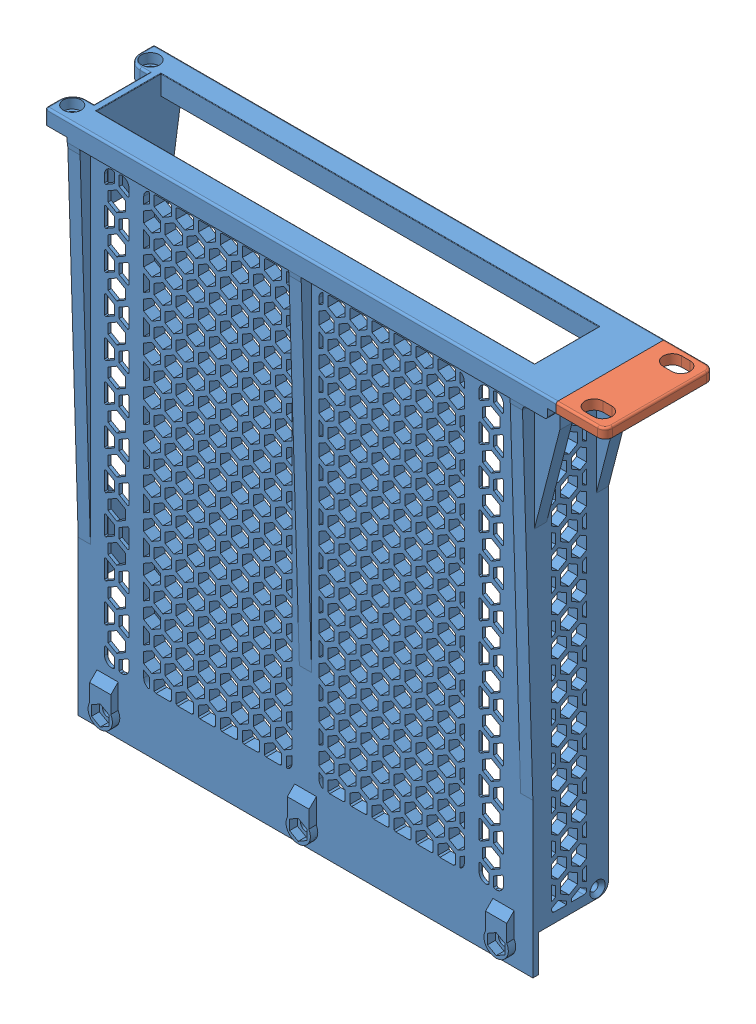
SolidWorks assembly Right Bracket (With Ear), configuration Standard. Lengths in mm.
Overall size (228.92 213 44.5).
2 component instances, 2 part files, 6 mates.
Components (placement in the parent):
- Right Bracket (With Ear)-1: Right Bracket (With Ear) [Standard] at (55.0369 -294.4118 21.21) size (208.92 213 44.5)
- Right Ear-1: Right Ear [Standard] at (55.0369 -294.4118 21.21) size (20 4 44.5)
Mates (geometry in assembly coordinates):
- Deckungsgleich1: coincident aligned: plane of Right Bracket (With Ear)-1 through (19 0 -22.25) normal (0 1 0); plane of Right Ear-1 through (19 0 -22.25) normal (0 1 0)
- Deckungsgleich2: coincident aligned: plane of Right Bracket (With Ear)-1 through (19 -4.4 0) normal (0 0 1); plane of Right Ear-1 through (19 -4.4 0) normal (0 0 1)
- Deckungsgleich3: coincident anti-aligned: plane of Right Bracket (With Ear)-1 through (199.75 -106.4994 -22.25) normal (1 0 0); plane of Right Ear-1 through (199.75 -106.4994 -22.25) normal (-1 0 0)
- Deckungsgleich4: coincident aligned: plane of ? through (19 -4.4 0) normal (0 0 1)
- Deckungsgleich5: coincident aligned: plane of ? through (19 0 -22.25) normal (0 1 0)
- Deckungsgleich6: coincident anti-aligned: plane of ? through (0 -181.8827 9.4707) normal (-1 0 0)
